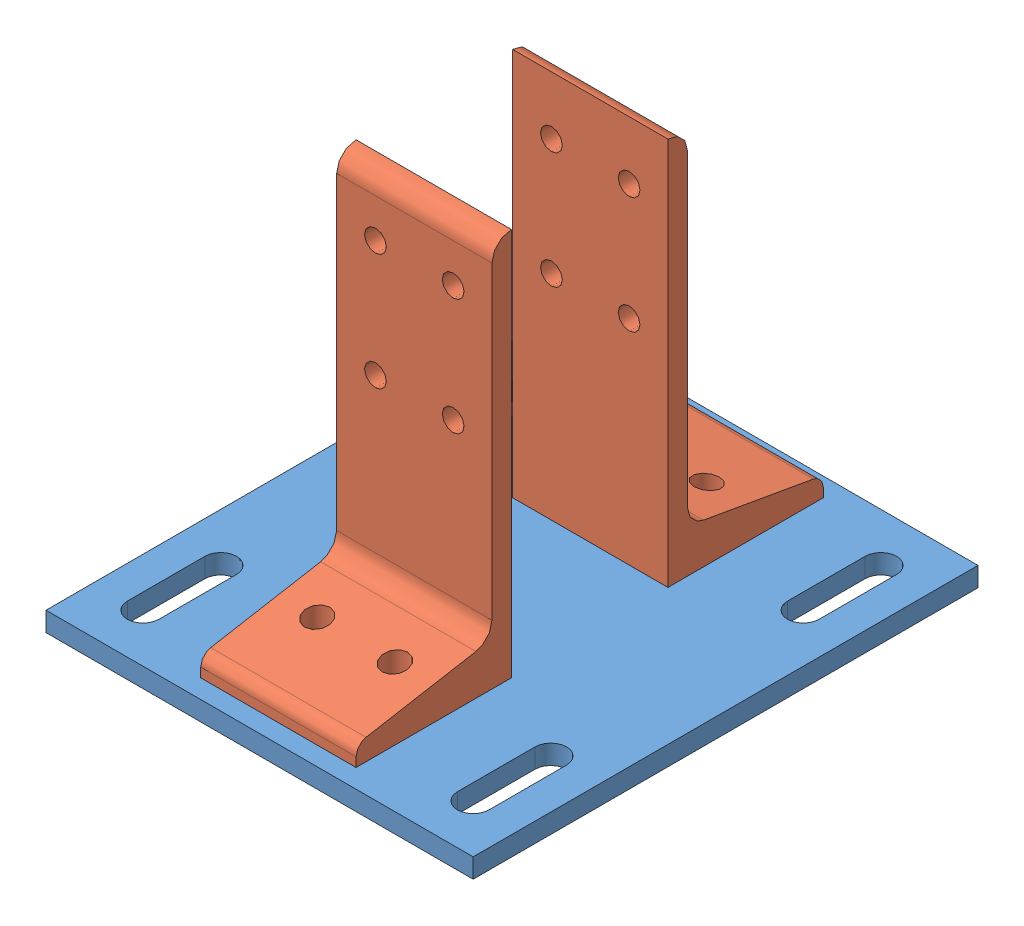
SolidWorks assembly 8020-2387-DEFAULT, configuration Default. Lengths in mm.
Overall size (139.7 133.35 165.1).
3 component instances, 2 part files, 0 mates.
Components (placement in the parent):
- 8020-2387-DEFAULT_238708-1: 8020-2387-DEFAULT_238708 [Default] at (-67.1549 7.3704 27.8119) size (139.7 6.35 165.1)
- 8020-2387-DEFAULT_238509-1: 8020-2387-DEFAULT_238509 [Default] at (9.1264 0.0214 49.7635) x (0 0 1) z (-1 0 0) size (50.8 127 50.8)
- 8020-2387-DEFAULT_238509-2: 8020-2387-DEFAULT_238509 [Default] at (-41.6736 0.0214 -46.9187) x (0 0 -1) z (1 0 0) size (50.8 127 50.8)
